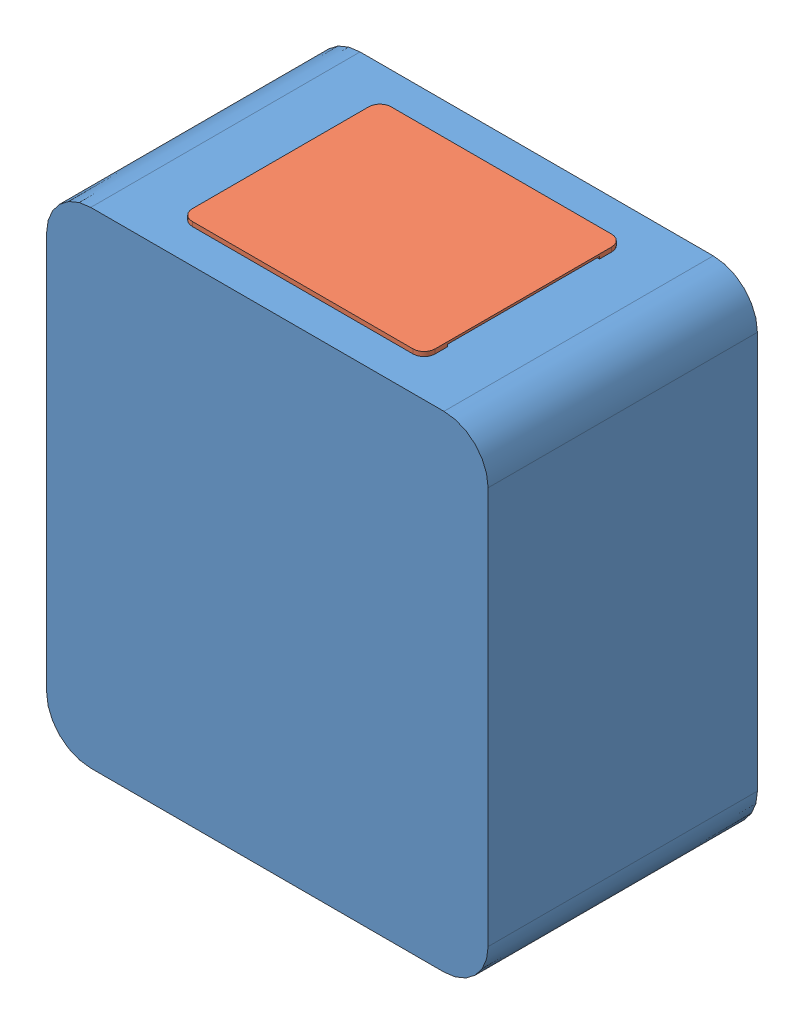
SolidWorks assembly RR-04-Reservior_Assem_2, configuration Default. Lengths in mm.
Overall size (200 222 134.7).
2 component instances, 2 part files, 4 mates.
Components (placement in the parent):
- reservoir_tank_v2-1: reservoir_tank_v2 [Default] at origin size (200 220 134.7)
- reservoir_lid_v2-1: reservoir_lid_v2 [Default] at (-18.1152 123.7537 59.5) size (110 5 90)
Mates (geometry in assembly coordinates):
- Coincident1: coordinate: point of reservoir_tank_v2-1
- Coincident2: coincident anti-aligned: plane of reservoir_tank_v2-1 through (31.3848 124.7537 19) normal (-1 0 0); plane of reservoir_lid_v2-1 through (31.3848 126.7537 20) normal (1 0 0)
- Coincident3: coincident anti-aligned: plane of reservoir_tank_v2-1 through (-68.6152 124.7537 99) normal (0 0 -1); plane of reservoir_lid_v2-1 through (-67.6152 126.7537 99) normal (0 0 1)
- Coincident4: coincident anti-aligned: plane of reservoir_tank_v2-1 through (-98.6152 126.7537 120) normal (0 1 0); plane of reservoir_lid_v2-1 through (-18.1152 126.7537 59.5) normal (0 -1 0)
